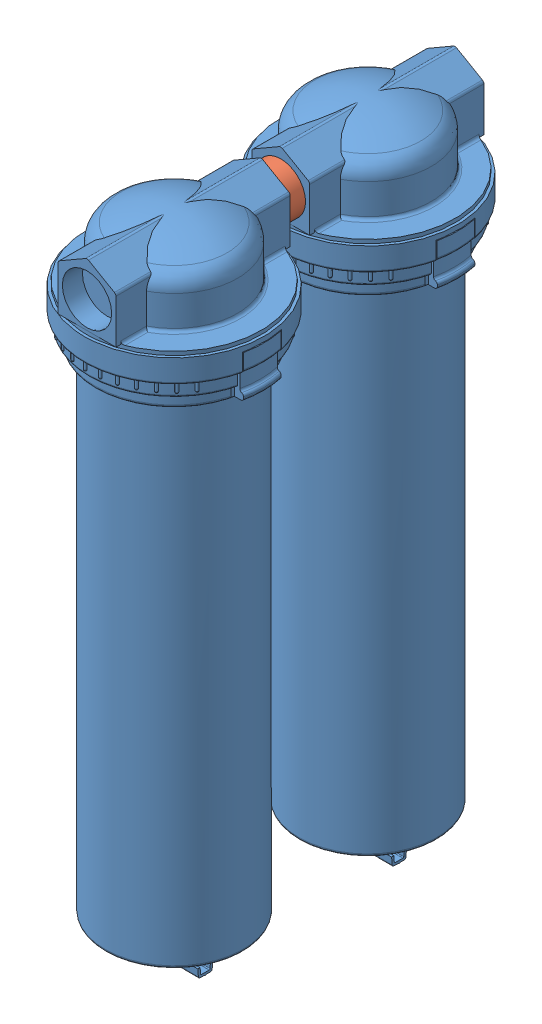
SolidWorks assembly ReadingTech_4P-150-M08-DCP, configuration Default. Lengths in mm.
Overall size (121.86 439.41 252.73).
3 component instances, 2 part files, 3 mates.
Components (placement in the parent):
- ReadingTech_3P-150-M08-P-1: ReadingTech_3P-150-M08-P [Default] at (-31.4816 -181.5268 8.5714) size (121.86 439.41 121.67)
- ReadingTech_3P-150-M08-P-2: ReadingTech_3P-150-M08-P [Default] at (-31.4816 -181.5268 -122.4926) size (121.86 439.41 121.67)
- ReadingTech- 90,150cfm_connector_1in-1: ReadingTech- 90,150cfm_connector_1in [Default] at (-31.4816 207.4742 -50.3566) x (1 0 0) z (0 1 0) size (33.4 13.21 33.4)
Mates (geometry in assembly coordinates):
- Coincident1: coincident anti-aligned: circle of ReadingTech_3P-150-M08-P-2; circle of ReadingTech- 90,150cfm_connector_1in-1
- Coincident2: coincident aligned: circle of ReadingTech_3P-150-M08-P-1; circle of ReadingTech- 90,150cfm_connector_1in-1
- Coincident3: coincident aligned: plane of ReadingTech_3P-150-M08-P-1 through (-11.9236 220.1742 67.4994) normal (1 0 0); plane of ReadingTech_3P-150-M08-P-2 through (-11.9236 220.1742 -63.5646) normal (1 0 0)
